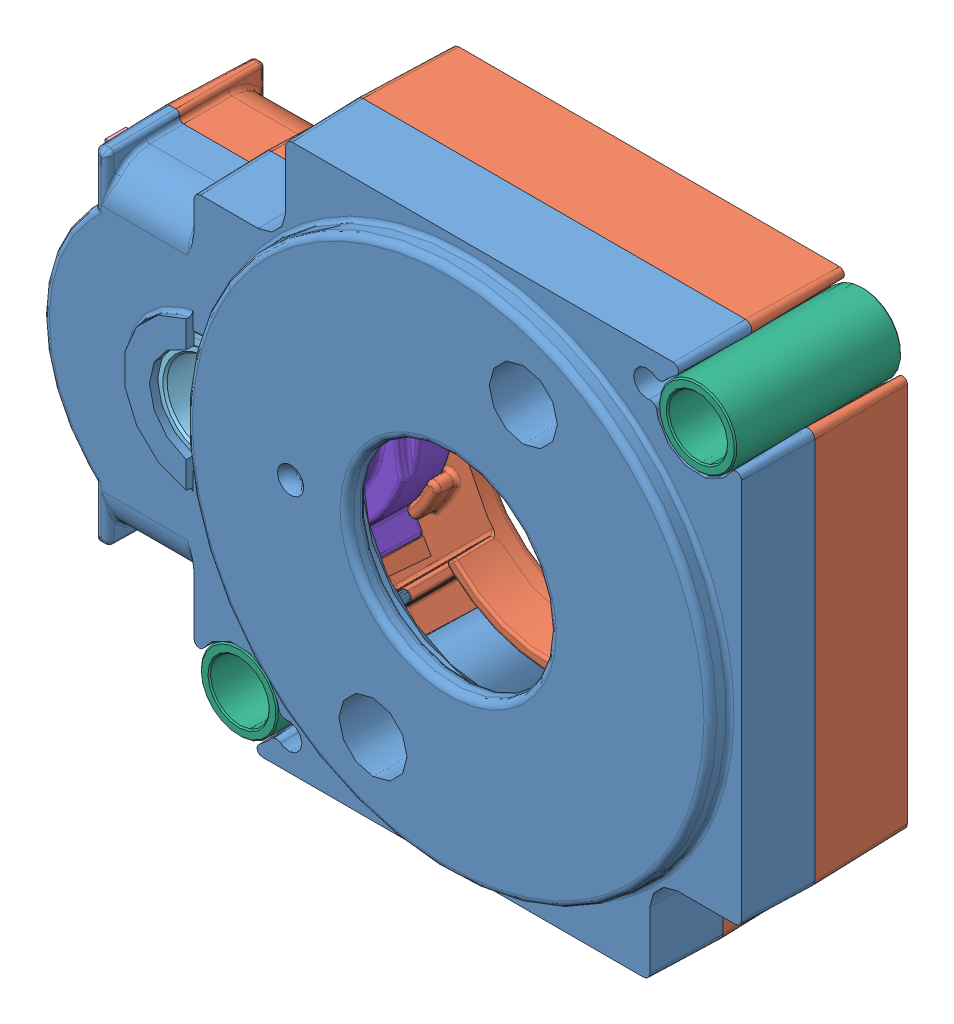
SolidWorks assembly VersaPlanetary_Integrated_Encoder_217-5046, configuration Default. Lengths in mm.
Overall size (58.06 43.13 18.16).
9 component instances, 8 part files, 0 mates.
Components (placement in the parent):
- 217-4783-001 Rev3-1: 217-4783-001 Rev3 [Default] at (0 0 2.75) size (53.55 42 11.11)
- 217-4783-002 Rev7_Sealed Config-1: 217-4783-002 Rev7_Sealed Config [Default] at (0 0 -7.2) x (0 1 0) z (0 0 1) size (42 51.56 9.32)
- 217-4783-008 Rev2-1: 217-4783-008 Rev2 [Default] at (-20.05 0 2.2) x (0.307149 -0.951661 0) z (0.951661 0.307149 0) size (5 4 5)
- PCBA Rev3-1: PCBA Rev3 [Default] at (-20.05 0 -2.1252) x (0 1 0) z (-1 0 0) size (15.93 10.15 24.44)
- 217-2788-001 Rev3_57155K375-1: 217-2788-001 Rev3_57155K375 [Default] at (-20.05 0 3.8125) x (-0.99574 0.092202 0) z (0 0 1) size (9.53 9.53 3.17)
- 217-4783-006 Rev3-1: 217-4783-006 Rev3 [Default] at (17.5 17.5 -0.85) x (-0.867641 0.497191 0) z (0 0 1) size (5.9 5.9 12.7)
- 217-4783-006 Rev3-2: 217-4783-006 Rev3 [Default] at (-17.5 -17.5 -0.85) x (0.825154 -0.564908 0) z (0 0 1) size (5.9 5.9 12.7)
- 217-4783-007 Rev1-1: 217-4783-007 Rev1 [Default] at (-16.45 0 -5.2) x (0 1 0) z (0 0 1) size (6 10.71 3.56)
- 217-4783-003 Rev4-1: 217-4783-003 Rev4 [Default] at (-20.05 0 -1.02) x (0 1 0) z (0 0 1) size (23.4 21.71 4.21)
